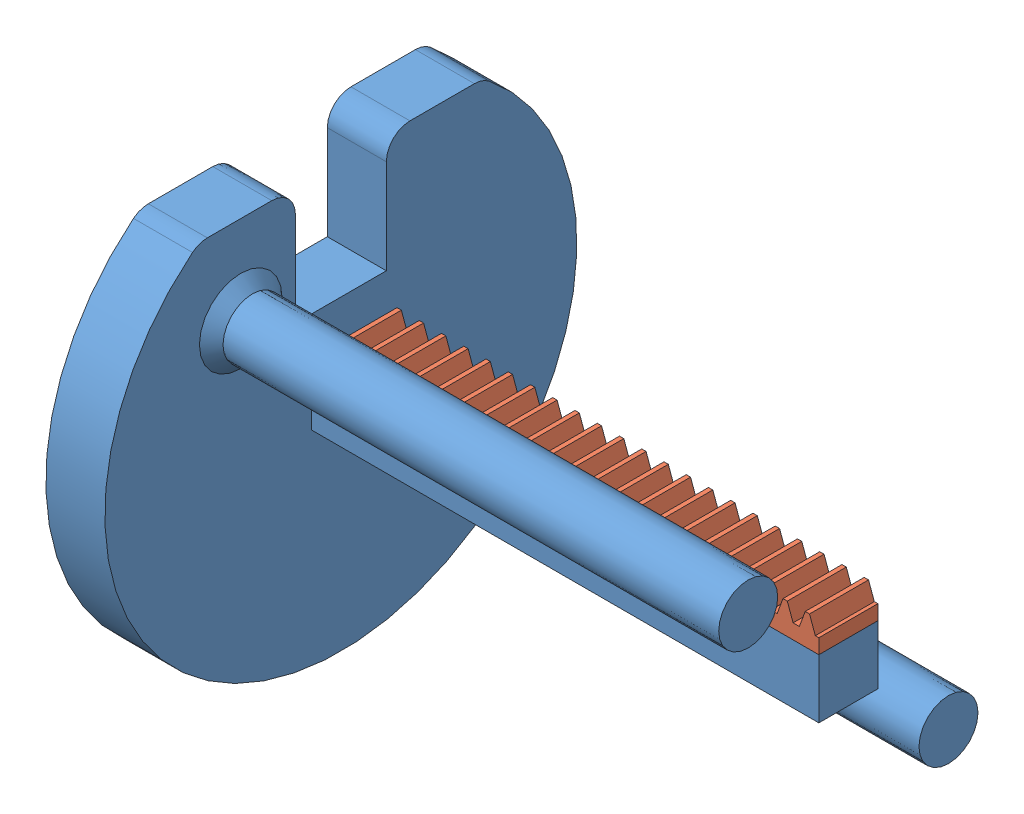
SolidWorks assembly Plunger, configuration Default. Lengths in mm.
Overall size (48 36 40).
2 component instances, 2 part files, 3 mates.
Components (placement in the parent):
- Rack Plunger-1: Rack Plunger [Default] at (1.5859 23.0032 35.546) size (48 36 40)
- rack spur rectangular_am-1: rack spur rectangular_am [Metric - Rack-spur - rectangular 0.6M 20PA 5FW 2PH 41.5L---SAll] at (8.0859 25.5032 38.046) size (41.5 2.6 5)
Mates (geometry in assembly coordinates):
- Coincident1: coincident aligned: plane of Rack Plunger-1 through (49.5859 20.5032 33.046) normal (0 0 -1); plane of rack spur rectangular_am-1 through (8.0859 28.1032 33.046) normal (0 0 -1)
- Coincident2: coincident aligned: plane of Rack Plunger-1 through (49.5859 23.0032 35.546) normal (1 0 0); plane of rack spur rectangular_am-1 through (49.5859 25.5032 33.046) normal (1 0 0)
- Coincident3: coincident anti-aligned: plane of Rack Plunger-1 through (49.5859 25.5032 38.046) normal (0 1 0); plane of rack spur rectangular_am-1 through (8.0859 25.5032 33.046) normal (0 -1 0)
